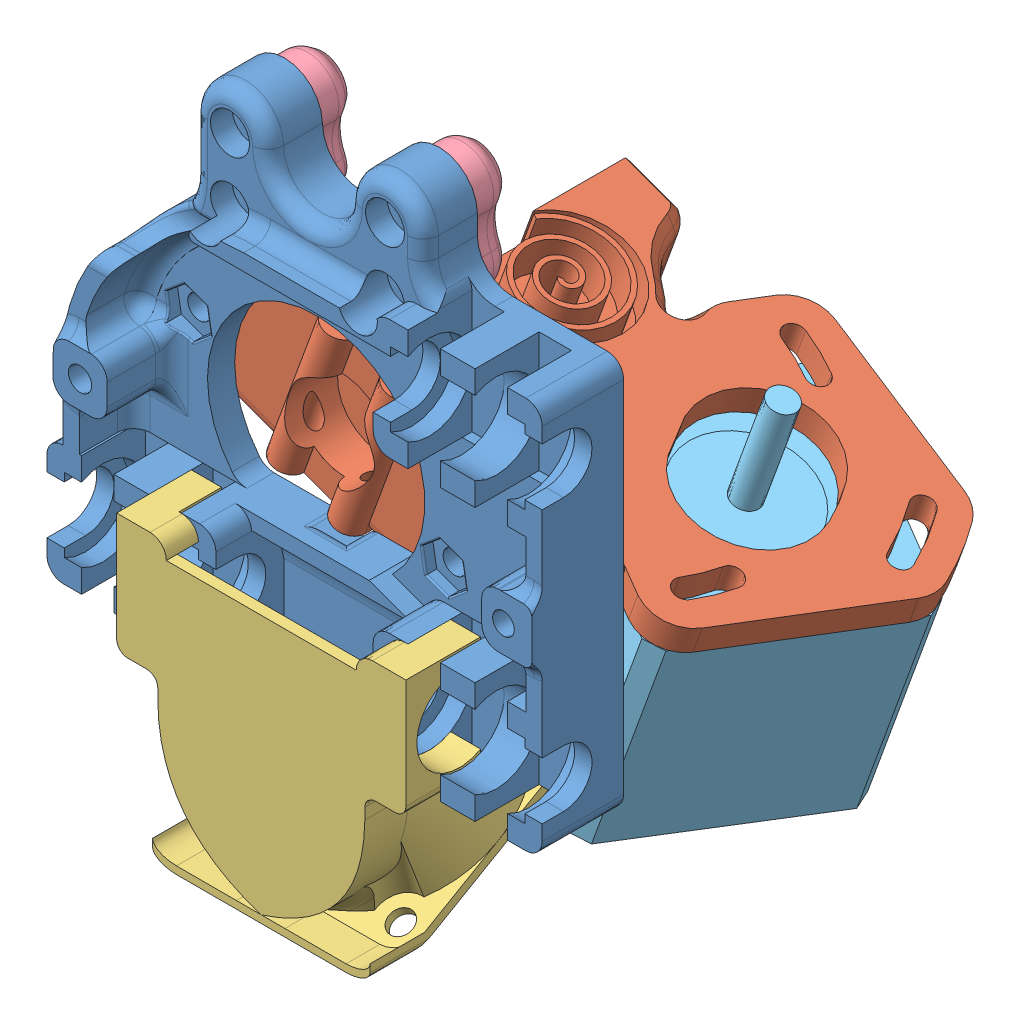
SolidWorks assembly NoHookAssembly, configuration Default. Lengths in mm.
Overall size (117.66 119.29 78.95).
6 component instances, 5 part files, 15 mates.
Components (placement in the parent):
- xCarriage_frontbelt_NoHook-1: xCarriage_frontbelt_NoHook [Default] at (33.1076 -15.6317 -6.8505) size (91.12 91.95 18.23)
- Eckstruder-16mm-insert-NoHook-1: Eckstruder-16mm-insert-NoHook [Default] at (72.2588 -11.4628 -6.8505) x (-0.939693 0.34202 0) z (-0.34202 -0.939693 0) size (102.08 61.05 28.5)
- Fan_Cowl-1: Fan_Cowl [Default] at (2.4515 -46.7215 14.0495) x (0 1 0) z (0 0 -1) size (52.24 53.22 41.97)
- BeltClamp-1: BeltClamp [Default] at (-14.7039 37.1837 -6.8505) x (0 1 0) z (0 0 1) size (23.1 11.5 7)
- BeltClamp-2: BeltClamp [Default] at (13.7952 37.184 -6.8505) x (0 1 0) z (0 0 1) size (23.1 11.5 7)
- Nema17_60ozin-1: Nema17_60ozin [Default] at (27.1247 -42.9233 -36.0452) x (0.361293 -0.1315 -0.923133) z (0.34202 0.939693 0) size (43 43 62)
Mates (geometry in assembly coordinates):
- Coincident1: coincident anti-aligned: plane of xCarriage_frontbelt_NoHook-1 through (-3.3485 0.0933 -6.8505) normal (0 0 -1); plane of Eckstruder-16mm-insert-NoHook-1 through (72.2588 -11.4628 -6.8505) normal (0 0 1)
- Concentric5: concentric anti-aligned: cylinder of xCarriage_frontbelt_NoHook-1 through (-3.3485 0.0933 -6.8505) axis (0 0 1) radius 20; cylinder of Eckstruder-16mm-insert-NoHook-1 through (-3.3485 0.0933 17.1495) axis (0 0 -1) radius 8.1
- Parallel1: parallel anti-aligned: line of Eckstruder-16mm-insert-NoHook-1 through (4.6009 13.1626 -6.8505) axis (-0.939693 0.34202 0); line of assembly
- Parallel3: parallel aligned: plane of xCarriage_frontbelt_NoHook-1 through (-3.3485 0.0933 -1.8505) normal (0 0 1); plane of Fan_Cowl-1 through (2.4515 -46.7215 14.0495) normal (0 0 1)
- Parallel2: parallel aligned: plane of xCarriage_frontbelt_NoHook-1 through (-17.6704 -13.8667 -6.8505) normal (0 1 0); plane of Fan_Cowl-1 through (-15.0085 -16.8667 14.0495) normal (0 1 0)
- Concentric9: concentric aligned: cylinder of xCarriage_frontbelt_NoHook-1 through (-15.0085 -24.9167 4.2095) axis (-1 0 0) radius 7.85; cylinder of Fan_Cowl-1 through (-18.6085 -24.9167 4.2095) axis (-1 0 0) radius 7.85
- Coincident3: coincident anti-aligned: plane of xCarriage_frontbelt_NoHook-1 through (-24.1585 -15.6317 -6.8505) normal (1 0 0); plane of Fan_Cowl-1 through (-24.1585 -11.8667 12.0495) normal (-1 0 0)
- Coincident4: coincident anti-aligned: plane of xCarriage_frontbelt_NoHook-1 through (-3.3485 0.0933 -6.8505) normal (0 0 -1); plane of BeltClamp-2 through (7.8797 43.284 -6.8505) normal (0 0 1)
- Coincident5: coincident anti-aligned: plane of xCarriage_frontbelt_NoHook-1 through (-3.3485 0.0933 -6.8505) normal (0 0 -1); plane of BeltClamp-1 through (-20.6194 43.2837 -6.8505) normal (0 0 1)
- Concentric10: concentric anti-aligned: cylinder of xCarriage_frontbelt_NoHook-1 through (14.2952 46.184 11.3773) axis (0 0 -1) radius 1.8; cylinder of BeltClamp-2 through (14.2952 46.184 -13.8505) axis (0 0 1) radius 1.8
- Concentric11: concentric anti-aligned: cylinder of xCarriage_frontbelt_NoHook-1 through (14.2952 34.584 11.3773) axis (0 0 -1) radius 1.8; cylinder of BeltClamp-2 through (14.2952 34.584 -13.8505) axis (0 0 1) radius 1.8
- Concentric12: concentric anti-aligned: cylinder of xCarriage_frontbelt_NoHook-1 through (-14.2039 46.1837 11.3773) axis (0 0 -1) radius 1.8; cylinder of BeltClamp-1 through (-14.2039 46.1837 -13.8505) axis (0 0 1) radius 1.8
- Concentric13: concentric anti-aligned: cylinder of xCarriage_frontbelt_NoHook-1 through (-14.2039 34.5837 11.3773) axis (0 0 -1) radius 1.8; cylinder of BeltClamp-1 through (-14.2039 34.5837 -13.8505) axis (0 0 1) radius 1.8
- Coincident6: coincident anti-aligned: plane of Eckstruder-16mm-insert-NoHook-1 through (70.5487 -16.1613 -11.8505) normal (-0.34202 -0.939693 0); plane of Nema17_60ozin-1 through (29.9228 -1.3747 -64.1589) normal (0.34202 0.939693 0)
- Concentric14: concentric aligned: cylinder of Eckstruder-16mm-insert-NoHook-1 through (42.5156 -0.6371 -36.0452) axis (-0.34202 -0.939693 0) radius 11.4; cylinder of Nema17_60ozin-1 through (41.4895 -3.4562 -36.0452) axis (-0.34202 -0.939693 0) radius 11
